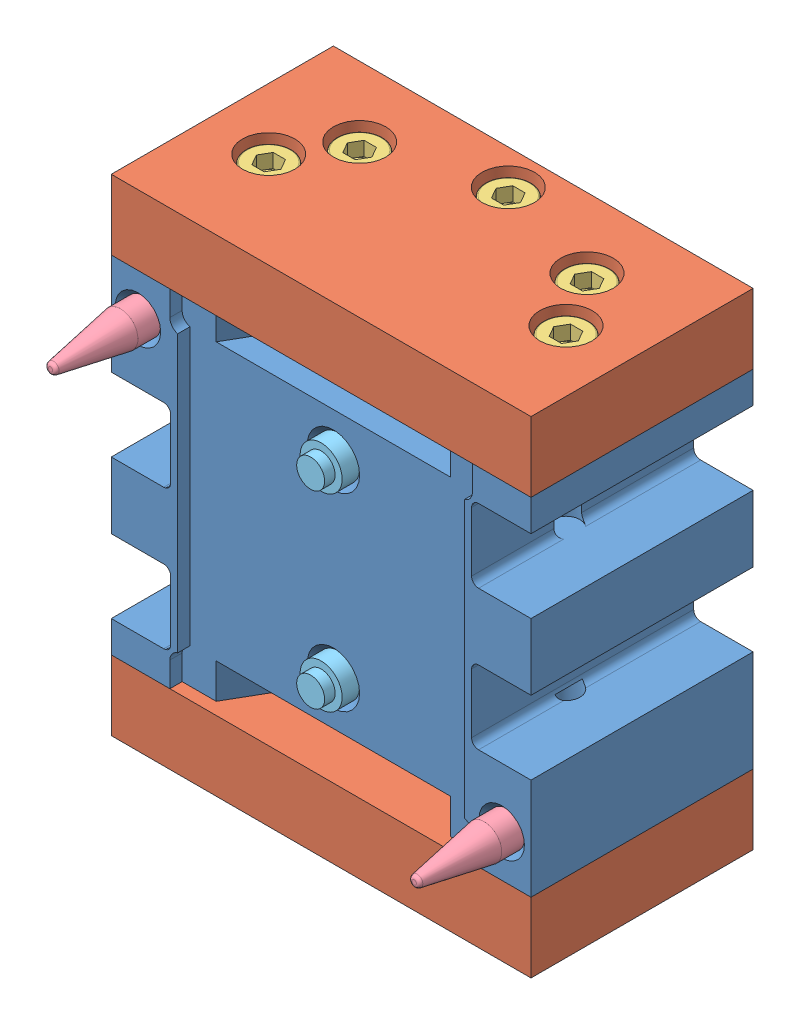
SolidWorks assembly ГТК 01.01.00 Сборка пресс-формы, configuration По умолчанию. Lengths in mm.
Overall size (120 139 88.5).
17 component instances, 5 part files, 34 mates.
Components (placement in the parent):
- ГТК 01.01.01 Матрица-1: ГТК 01.01.01 Матрица [По умолчанию] at origin size (120 99 63.5)
- ГТК 01.01.02 Боковина пресс-формы-1: ГТК 01.01.02 Боковина пресс-формы [По умолчанию] at (0 -49.5 31.75) x (1 0 0) z (0 -1 0) size (120 63.5 20)
- ISO 4762 М8x16-1: ISO 4762 М8x16 [ISO 4762 M8 x 16 - 16N] at (-42.5 -67.5 36) x (0 1 0) z (0 0 1) size (24 13 13)
- ISO 4762 М8x16-2: ISO 4762 М8x16 [ISO 4762 M8 x 16 - 16N] at (-32.5 -67.5 20) x (0 1 0) z (0 0 1) size (24 13 13)
- ISO 4762 М8x16-3: ISO 4762 М8x16 [ISO 4762 M8 x 16 - 16N] at (0 -67.5 10) x (0 1 0) z (0 0 1) size (24 13 13)
- ISO 4762 М8x16-4: ISO 4762 М8x16 [ISO 4762 M8 x 16 - 16N] at (32.5 -67.5 20) x (0 1 0) z (0 0 1) size (24 13 13)
- ISO 4762 М8x16-5: ISO 4762 М8x16 [ISO 4762 M8 x 16 - 16N] at (42.5 -67.5 36) x (0 1 0) z (0 0 1) size (24 13 13)
- ISO 4762 М8x16-11: ISO 4762 М8x16 [ISO 4762 M8 x 16 - 16N] at (-42.5 67.5 36) x (0 -1 0) z (0 0 1) size (24 13 13)
- ISO 4762 М8x16-12: ISO 4762 М8x16 [ISO 4762 M8 x 16 - 16N] at (-32.5 67.5 20) x (0 -1 0) z (0 0 1) size (24 13 13)
- ISO 4762 М8x16-13: ISO 4762 М8x16 [ISO 4762 M8 x 16 - 16N] at (0 67.5 10) x (0 -1 0) z (0 0 1) size (24 13 13)
- ISO 4762 М8x16-14: ISO 4762 М8x16 [ISO 4762 M8 x 16 - 16N] at (32.5 67.5 20) x (0 -1 0) z (0 0 1) size (24 13 13)
- ISO 4762 М8x16-15: ISO 4762 М8x16 [ISO 4762 M8 x 16 - 16N] at (42.5 67.5 36) x (0 -1 0) z (0 0 1) size (24 13 13)
- ГТК 01.01.02 Боковина пресс-формы-3: ГТК 01.01.02 Боковина пресс-формы [По умолчанию] at (0 49.5 31.75) x (-1 0 0) z (0 1 0) size (120 63.5 20)
- ГТК 01.01.03 Направляющая-1: ГТК 01.01.03 Направляющая [По умолчанию] at (-52.375 37.5 33.5) x (0 0 1) z (-0.953769 -0.300541 0) size (55 10 10)
- ГТК 01.01.03 Направляющая-2: ГТК 01.01.03 Направляющая [По умолчанию] at (51.625 -37.5 33.5) x (0 0 1) z (-0.599492 0.800381 0) size (55 10 10)
- ГТК 01.01.04 Втулка-1: ГТК 01.01.04 Втулка [По умолчанию] at (0 27 30) x (0 0 1) z (-0.845392 0.534146 0) size (36.5 12 12)
- ГТК 01.01.04 Втулка-2: ГТК 01.01.04 Втулка [По умолчанию] at (0 -27 30) x (0 0 1) z (-0.844306 0.535861 0) size (36.5 12 12)
Mates (geometry in assembly coordinates):
- Совпадение1: coincident anti-aligned: plane of ГТК 01.01.01 Матрица-1 through (-60 -49.5 63.5) normal (0 -1 0); plane of ГТК 01.01.02 Боковина пресс-формы-1 through (0 -49.5 31.75) normal (0 1 0)
- Концентричный1: concentric aligned: cylinder of ГТК 01.01.01 Матрица-1 through (42.5 -19.5 36) axis (0 -1 0) radius 4; cylinder of ГТК 01.01.02 Боковина пресс-формы-1 through (42.5 -49.5 36) axis (0 -1 0) radius 4
- Концентричный2: concentric aligned: cylinder of ГТК 01.01.01 Матрица-1 through (-42.5 -19.5 36) axis (0 -1 0) radius 4; cylinder of ГТК 01.01.02 Боковина пресс-формы-1 through (-42.5 -49.5 36) axis (0 -1 0) radius 4
- Концентричный3: concentric aligned: cylinder of ГТК 01.01.02 Боковина пресс-формы-1 through (-42.5 -49.5 36) axis (0 -1 0) radius 4; cylinder of socket head cap screw_iso-1 through (-42.5 -99.25 36) axis (0 -1 0) radius 6.5
- Совпадение2: coincident anti-aligned: plane of ГТК 01.01.02 Боковина пресс-формы-1 through (-42.5 -59.5 36) normal (0 -1 0); plane of socket head cap screw_iso-1 through (-49 -59.5 36) normal (0 1 0)
- Концентричный4: concentric aligned: cylinder of ГТК 01.01.02 Боковина пресс-формы-1 through (-32.5 -49.5 20) axis (0 -1 0) radius 4; cylinder of socket head cap screw_iso-2 through (-32.5 -99.25 20) axis (0 -1 0) radius 6.5
- Совпадение3: coincident anti-aligned: plane of ГТК 01.01.02 Боковина пресс-формы-1 through (-32.5 -59.5 20) normal (0 -1 0); plane of socket head cap screw_iso-2 through (-39 -59.5 20) normal (0 1 0)
- Концентричный5: concentric aligned: cylinder of ГТК 01.01.02 Боковина пресс-формы-1 through (0 -59.5 10) axis (0 -1 0) radius 7.5; cylinder of socket head cap screw_iso-3 through (0 -99.25 10) axis (0 -1 0) radius 6.5
- Совпадение4: coincident anti-aligned: plane of ГТК 01.01.02 Боковина пресс-формы-1 through (0 -59.5 10) normal (0 -1 0); plane of socket head cap screw_iso-3 through (-6.5 -59.5 10) normal (0 1 0)
- Концентричный6: concentric aligned: cylinder of ГТК 01.01.02 Боковина пресс-формы-1 through (32.5 -59.5 20) axis (0 -1 0) radius 7.5; cylinder of socket head cap screw_iso-4 through (32.5 -99.25 20) axis (0 -1 0) radius 6.5
- Совпадение5: coincident anti-aligned: plane of ГТК 01.01.02 Боковина пресс-формы-1 through (32.5 -59.5 20) normal (0 -1 0); plane of socket head cap screw_iso-4 through (26 -59.5 20) normal (0 1 0)
- Концентричный7: concentric aligned: cylinder of ГТК 01.01.02 Боковина пресс-формы-1 through (42.5 -59.5 36) axis (0 -1 0) radius 7.5; cylinder of socket head cap screw_iso-5 through (42.5 -99.25 36) axis (0 -1 0) radius 6.5
- Совпадение6: coincident anti-aligned: plane of ГТК 01.01.02 Боковина пресс-формы-1 through (42.5 -59.5 36) normal (0 -1 0); plane of socket head cap screw_iso-5 through (36 -59.5 36) normal (0 1 0)
- Совпадение7: coincident anti-aligned: plane of ГТК 01.01.01 Матрица-1 through (-60 49.5 63.5) normal (0 1 0); plane of ГТК 01.01.02 Боковина пресс-формы-3 through (0 49.5 31.75) normal (0 -1 0)
- Концентричный8: concentric aligned: cylinder of ГТК 01.01.01 Матрица-1 through (-42.5 19.5 36) axis (0 1 0) radius 4; cylinder of ГТК 01.01.02 Боковина пресс-формы-3 through (-42.5 49.5 36) axis (0 1 0) radius 4
- Концентричный9: concentric aligned: cylinder of ГТК 01.01.01 Матрица-1 through (42.5 19.5 36) axis (0 1 0) radius 4; cylinder of ГТК 01.01.02 Боковина пресс-формы-3 through (42.5 49.5 36) axis (0 1 0) radius 4
- Концентричный10: concentric aligned: cylinder of ГТК 01.01.02 Боковина пресс-формы-3 through (-42.5 59.5 36) axis (0 1 0) radius 7.5; cylinder of socket head cap screw_iso-11 through (-42.5 99.25 36) axis (0 1 0) radius 6.5
- Совпадение8: coincident anti-aligned: plane of ГТК 01.01.02 Боковина пресс-формы-3 through (-42.5 59.5 36) normal (0 1 0); plane of socket head cap screw_iso-11 through (-36 59.5 36) normal (0 -1 0)
- Концентричный11: concentric aligned: cylinder of ГТК 01.01.02 Боковина пресс-формы-3 through (-32.5 49.5 20) axis (0 1 0) radius 4; cylinder of socket head cap screw_iso-12 through (-32.5 99.25 20) axis (0 1 0) radius 6.5
- Совпадение9: coincident anti-aligned: plane of ГТК 01.01.02 Боковина пресс-формы-3 through (-32.5 59.5 20) normal (0 1 0); plane of socket head cap screw_iso-12 through (-26 59.5 20) normal (0 -1 0)
- Концентричный12: concentric aligned: cylinder of ГТК 01.01.02 Боковина пресс-формы-3 through (0 49.5 10) axis (0 1 0) radius 4; cylinder of socket head cap screw_iso-13 through (0 99.25 10) axis (0 1 0) radius 6.5
- Совпадение10: coincident anti-aligned: plane of ГТК 01.01.02 Боковина пресс-формы-3 through (0 59.5 10) normal (0 1 0); plane of socket head cap screw_iso-13 through (6.5 59.5 10) normal (0 -1 0)
- Концентричный13: concentric aligned: cylinder of ГТК 01.01.02 Боковина пресс-формы-3 through (32.5 49.5 20) axis (0 1 0) radius 4; cylinder of socket head cap screw_iso-14 through (32.5 99.25 20) axis (0 1 0) radius 6.5
- Совпадение11: coincident anti-aligned: plane of ГТК 01.01.02 Боковина пресс-формы-3 through (32.5 59.5 20) normal (0 1 0); plane of socket head cap screw_iso-14 through (39 59.5 20) normal (0 -1 0)
- Концентричный14: concentric aligned: cylinder of ГТК 01.01.02 Боковина пресс-формы-3 through (42.5 49.5 36) axis (0 1 0) radius 4; cylinder of socket head cap screw_iso-15 through (42.5 99.25 36) axis (0 1 0) radius 6.5
- Совпадение12: coincident anti-aligned: plane of ГТК 01.01.02 Боковина пресс-формы-3 through (42.5 59.5 36) normal (0 1 0); plane of socket head cap screw_iso-15 through (49 59.5 36) normal (0 -1 0)
- Концентричный15: concentric anti-aligned: cylinder of ГТК 01.01.01 Матрица-1 through (-52.375 37.5 33.5) axis (0 0 1) radius 5; cylinder of ГТК 01.01.03 Направляющая-1 through (-52.375 37.5 33.5) axis (0 0 -1) radius 5
- Совпадение13: coincident anti-aligned: plane of ГТК 01.01.01 Матрица-1 through (-52.375 37.5 33.5) normal (0 0 1); plane of ГТК 01.01.03 Направляющая-1 through (-52.375 37.5 33.5) normal (0 0 -1)
- Концентричный16: concentric anti-aligned: cylinder of ГТК 01.01.01 Матрица-1 through (51.625 -37.5 33.5) axis (0 0 1) radius 5; cylinder of ГТК 01.01.03 Направляющая-2 through (51.625 -37.5 33.5) axis (0 0 -1) radius 5
- Совпадение14: coincident anti-aligned: plane of ГТК 01.01.01 Матрица-1 through (51.625 -37.5 33.5) normal (0 0 1); plane of ГТК 01.01.03 Направляющая-2 through (51.625 -37.5 33.5) normal (0 0 -1)
- Концентричный18: concentric aligned: cylinder of ГТК 01.01.01 Матрица-1 through (0 27 30) axis (0 0 1) radius 6; cylinder of ГТК 01.01.04 Втулка-1 through (0 27 66.5) axis (0 0 1) radius 6
- Совпадение15: coincident anti-aligned: plane of ГТК 01.01.01 Матрица-1 through (0 27 30) normal (0 0 1); plane of ГТК 01.01.04 Втулка-1 through (0 27 30) normal (0 0 -1)
- Концентричный19: concentric aligned: cylinder of ГТК 01.01.01 Матрица-1 through (0 -27 30) axis (0 0 1) radius 6; cylinder of ГТК 01.01.04 Втулка-2 through (0 -27 66.5) axis (0 0 1) radius 6
- Совпадение16: coincident anti-aligned: plane of ГТК 01.01.01 Матрица-1 through (0 -27 30) normal (0 0 1); plane of ГТК 01.01.04 Втулка-2 through (0 -27 30) normal (0 0 -1)
